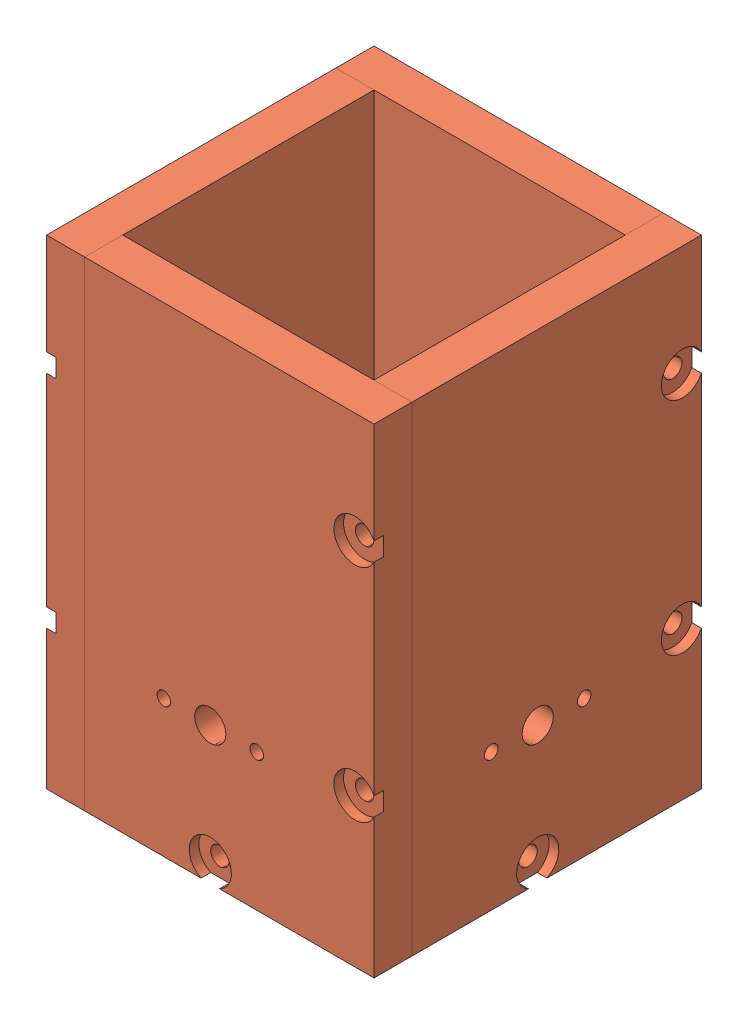
SolidWorks assembly waveguide_antenna_v1, configuration Default. Lengths in mm.
Overall size (43 63 43).
5 component instances, 2 part files, 10 mates.
Components (placement in the parent):
- backplate-1: backplate [Default] at origin size (33 5 33)
- sidewall-2: sidewall [Default] at (-21.5 31.5 2.5) x (0 -1 0) z (0 0 1) size (63 5 38)
- sidewall-3: sidewall [Default] at (2.5 31.5 21.5) x (0 -1 0) z (1 0 0) size (63 5 38)
- sidewall-4: sidewall [Default] at (21.5 31.5 -2.5) x (0 -1 0) z (0 0 -1) size (63 5 38)
- sidewall-6: sidewall [Default] at (-2.5 31.5 -21.5) x (0 -1 0) z (-1 0 0) size (63 5 38)
Mates (geometry in assembly coordinates):
- Concentric1: concentric aligned: circle of backplate-1; circle of sidewall-2
- Coincident1: coincident anti-aligned: line of backplate-1 through (-16.5 0 -16.5) axis (0 0 1); line of sidewall-2 through (-16.5 0 21.5) axis (0 0 -1)
- Concentric2: concentric aligned: circle of backplate-1; circle of sidewall-3
- Coincident2: coincident anti-aligned: line of backplate-1 through (-16.5 0 16.5) axis (1 0 0); line of sidewall-3 through (21.5 0 16.5) axis (-1 0 0)
- Concentric3: concentric aligned: circle of backplate-1; circle of sidewall-4
- Parallel1: parallel anti-aligned: line of sidewall-3 through (21.5 47.2869 21.5) axis (0 -1 0); line of sidewall-4 through (16.5 0 16.5) axis (0 1 0)
- Coincident6: coincident anti-aligned: line of backplate-1 through (16.5 0 16.5) axis (0 0 -1); line of sidewall-4 through (16.5 0 -21.5) axis (0 0 1)
- Concentric4: concentric aligned: circle of backplate-1; circle of sidewall-6
- Coincident9: coincident: plane of sidewall-2 through (-21.5 31.5 2.5) normal (-1 0 0); line of sidewall-6 through (-21.5 63 -16.5) axis (0 -1 0)
- Coincident10: coincident anti-aligned: line of sidewall-2 through (-21.5 0 -16.5) axis (0 1 0); line of sidewall-6 through (-21.5 63 -16.5) axis (0 -1 0)
